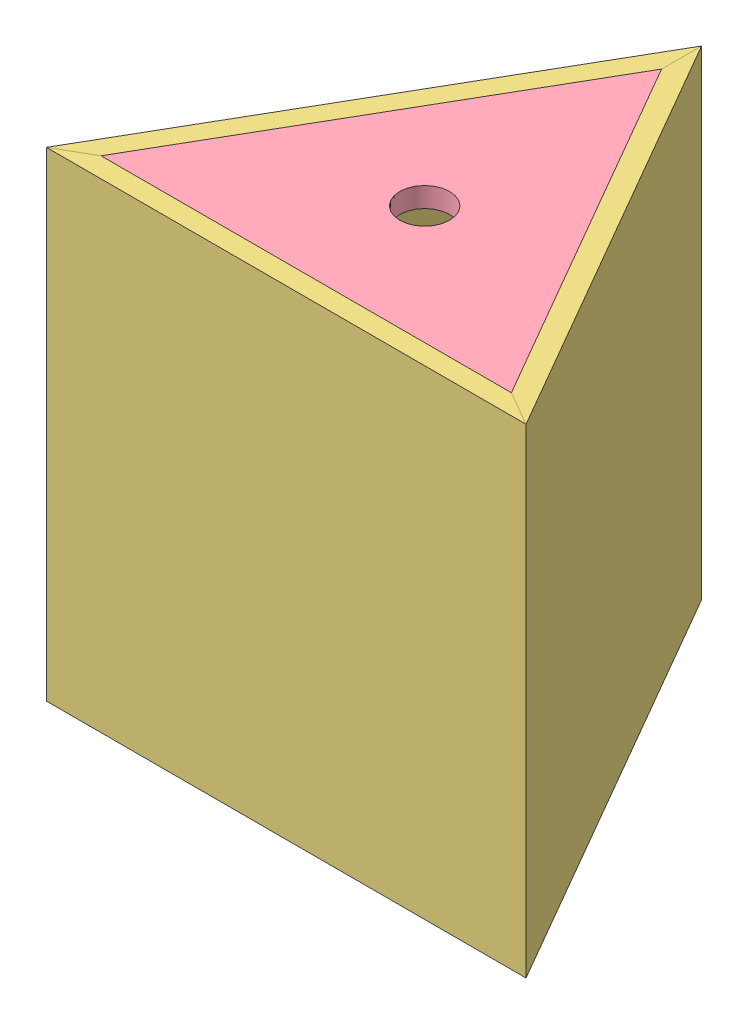
SolidWorks assembly triangle_and_washers, configuration Default. Lengths in mm.
Overall size (348 323.85 364.2).
15 component instances, 5 part files, 8 mates.
Components (placement in the parent):
- collar-1: collar [Default] at (977.2141 748.0151 2218.518) size (44.45 12.7 44.45)
- washer-1: washer [Default] at (977.2141 760.7151 2218.518) size (82.55 3.17 82.55)
- triangle-1: triangle [Default] at (859.8458 525.4427 2574.5415) x (1 0 0) z (0 1 0) size (348 364.2 304.8)
  - triangle_face-1: triangle_face [Default] at (-35.0317 268.0353 238.4474) size (304.8 12.7 304.8)
  - triangle_face-2: triangle_face [Default] at (117.3683 531.9998 238.4474) x (-0.5 -0.866025 0) z (0 0 1) size (304.8 12.7 304.8)
  - triangle_face-3: triangle_face [Default] at (269.7683 268.0353 238.4474) x (-0.5 0.866025 0) z (0 0 1) size (304.8 12.7 304.8)
  - triangle_top_bot-1: triangle_top_bot [Default] at (269.7683 268.0353 238.4474) x (0.5 -0.866025 0) z (0 0 -1) size (260.81 225.86 12.7)
  - triangle_top_bot-2: triangle_top_bot [Default] at (269.7683 268.0353 543.2474) size (260.81 225.86 12.7)
  - triangle_inside_corner-1: triangle_inside_corner [Default] at (53.355 472.7151 492.4474) x (0.5 -0.866025 0) z (-0.866025 -0.5 0) size (83.58 38.1 72.38)
  - triangle_inside_corner-2: triangle_inside_corner [Default] at (48.317 242.2404 492.4474) x (0.5 0.866025 0) z (0.866025 -0.5 0) size (83.58 38.1 72.38)
  - triangle_inside_corner-3: triangle_inside_corner [Default] at (225.5462 242.2404 492.4474) x (0.5 0.866025 0) z (0.866025 -0.5 0) size (83.58 38.1 72.38)
  - triangle_inside_corner-4: triangle_inside_corner [Default] at (48.317 242.2404 251.1474) x (0.5 0.866025 0) z (0.866025 -0.5 0) size (83.58 38.1 72.38)
  - triangle_inside_corner-6: triangle_inside_corner [Default] at (225.5462 242.2404 251.1474) x (0.5 0.866025 0) z (0.866025 -0.5 0) size (83.58 38.1 72.38)
  - triangle_inside_corner-7: triangle_inside_corner [Default] at (53.355 472.7151 251.1474) x (0.5 -0.866025 0) z (-0.866025 -0.5 0) size (83.58 38.1 72.38)
- washer-2: washer [Default] at (977.2141 744.8401 2218.518) size (82.55 3.17 82.55)
Mates (geometry in assembly coordinates):
- Concentric1: concentric aligned: circle of collar-1; circle of washer-1
- Concentric2: concentric aligned: circle of rod-1; circle of washer-1
- Concentric3: concentric anti-aligned: circle of rod-1; circle of triangle-1/triangle_top_bot-1
- Distance1: distance = 38.1 mm aligned: plane of collar-1 through (977.2141 748.0151 2218.518) normal (0 -1 0); plane of rod-1 through (977.2141 709.9151 2218.518) normal (0 -1 0)
- Coincident2: coincident anti-aligned: plane of collar-1 through (977.2141 760.7151 2218.518) normal (0 1 0); plane of washer-1 through (977.2141 760.7151 2218.518) normal (0 -1 0)
- Coincident3: coincident anti-aligned: plane of washer-1 through (977.2141 763.8901 2218.518) normal (0 1 0); plane of triangle-1/triangle_top_bot-1 through (1129.6141 763.8901 2306.5062) normal (0 -1 0)
- Concentric4: concentric aligned: circle of collar-1; circle of washer-2
- Coincident5: coincident anti-aligned: plane of collar-1 through (977.2141 748.0151 2218.518) normal (0 -1 0); plane of washer-2 through (977.2141 748.0151 2218.518) normal (0 1 0)
